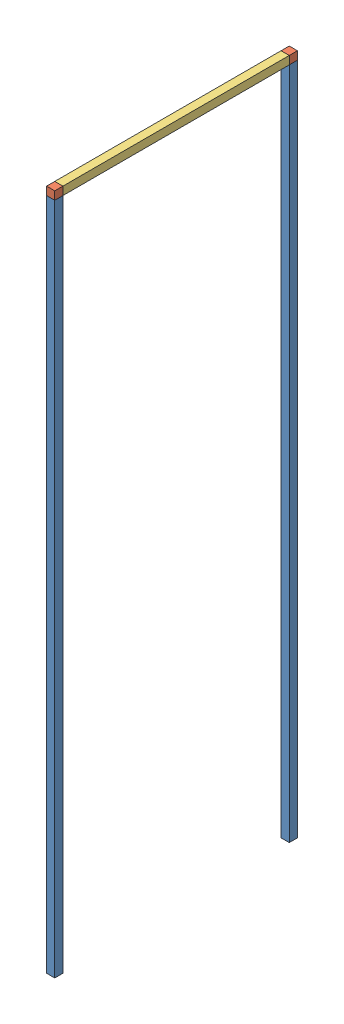
SolidWorks assembly Assem2, configuration Default. Lengths in mm.
Overall size (30 2510 890).
5 component instances, 3 part files, 8 mates.
Components (placement in the parent):
- Part2_1-1: Part2_1 [Default] at (469.6634 -65.8341 2247.6088) size (30 2480 30)
- Part2_1-2: Part2_1 [Default] at (469.6634 -65.8341 1387.6088) size (30 2480 30)
- Part2_2-1: Part2_2 [Default] at (454.6634 2419.1659 2217.6088) x (0 1 0) z (0 0 -1) size (30 30 30)
- Part2_2-2: Part2_2 [Default] at (469.6634 2404.1659 1387.6088) size (30 30 30)
- Part2_3-3: Part2_3 [Default] at (469.6634 2404.1659 2217.6088) size (30 30 840)
Mates (geometry in assembly coordinates):
- Coincident4: coincident anti-aligned: line of Part2_1-1 through (484.6634 2404.1659 2217.6088) axis (0 0 1); line of Part2_2-1 through (484.6634 2404.1659 2247.6088) axis (0 0 -1)
- Coincident5: coincident anti-aligned: line of Part2_1-1 through (484.6634 2404.1659 2247.6088) axis (-1 0 0); line of Part2_2-1 through (454.6634 2404.1659 2247.6088) axis (1 0 0)
- Coincident14: coincident anti-aligned: line of Part2_1-2 through (484.6634 2404.1659 1357.6088) axis (0 0 1); line of Part2_2-2 through (484.6634 2404.1659 1387.6088) axis (0 0 -1)
- Coincident16: coincident aligned: line of Part2_1-2 through (484.6634 2404.1659 1357.6088) axis (-1 0 0); line of Part2_2-2 through (484.6634 2404.1659 1357.6088) axis (-1 0 0)
- Coincident17: coincident anti-aligned: circle of Part2_2-2; circle of Part2_3-3
- Coincident18: coincident anti-aligned: circle of Part2_2-1; circle of Part2_3-3
- Coincident23: coincident anti-aligned: line of Part2_2-2 through (484.6634 2434.1659 1387.6088) axis (0 -1 0); line of Part2_3-3 through (484.6634 2404.1659 1387.6088) axis (0 1 0)
- Coincident26: coincident aligned: line of Part2_2-1 through (484.6634 2434.1659 2217.6088) axis (0 -1 0); line of Part2_3-3 through (484.6634 2434.1659 2217.6088) axis (0 -1 0)
